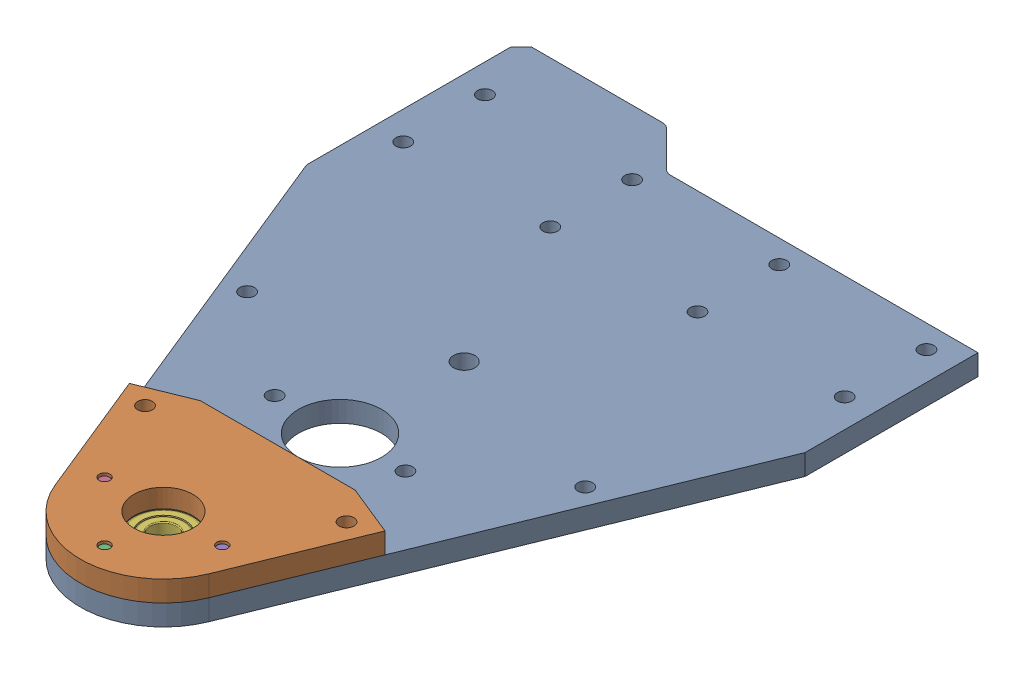
SolidWorks assembly Main Plate Sub Asmbly, configuration Default. Lengths in mm.
Overall size (152.4 12.84 210.99).
6 component instances, 4 part files, 0 mates.
Components (placement in the parent):
- Main Plate-1: Main Plate [Default] at origin size (152.4 6.35 210.99)
- Bearing Plate-1: Bearing Plate [Default] at origin size (78.15 6.35 60.33)
- 91294A192 - M4 x 0.7 mm, 12 mm Long Hex Drive Flat Head Screw-1: 91294A192 - M4 x 0.7 mm, 12 mm Long Hex Drive Flat Head Screw [Default] at (0 -33.3375 171.3144) x (1 0 0) z (0 -1 0) size (8 8 12.14)
- 91294A192 - M4 x 0.7 mm, 12 mm Long Hex Drive Flat Head Screw-2: 91294A192 - M4 x 0.7 mm, 12 mm Long Hex Drive Flat Head Screw [Default] at (-18 -33.3375 153.3144) x (1 0 0) z (0 -1 0) size (8 8 12.14)
- 91294A192 - M4 x 0.7 mm, 12 mm Long Hex Drive Flat Head Screw-3: 91294A192 - M4 x 0.7 mm, 12 mm Long Hex Drive Flat Head Screw [Default] at (18 -33.3375 153.3144) x (1 0 0) z (0 -1 0) size (8 8 12.14)
- 8x22x7+Bearing+-+6082Z-8x22x7_6082Z-8x22x7-1: 8x22x7+Bearing+-+6082Z-8x22x7_6082Z-8x22x7 [Default] at (0 -29.8375 153.3144) x (1 0 0) z (0 -1 0) size (22 22 7.01)
